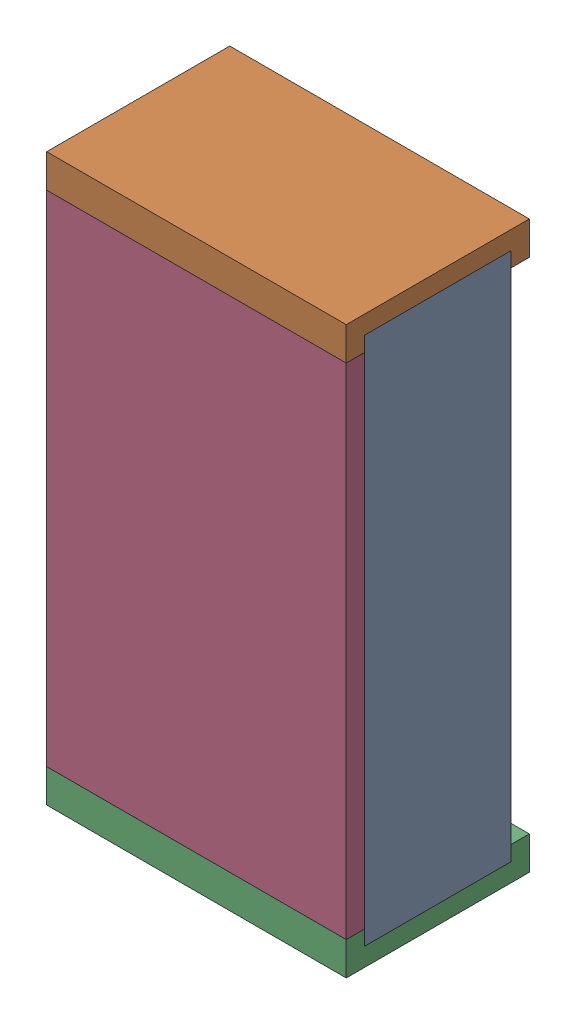
SolidWorks assembly R9, configuration Default. Lengths in mm.
Overall size (0.9 1.7 0.55).
7 component instances, 3 part files, 0 mates.
Components (placement in the parent):
- 6019289920-1: 6019289920 [Default] at (27.1701 -0.0001 0) x (0 -1 0) z (0 0 1) size (1.7 0.9 0.55)
  - Mid_Body_2-1: Mid_Body_2 [Default] at (-0.85 -0.45 0) size (1.59 0.9 0.44)
  - Terminal_2-1: Terminal_2 [Default] at (-0.85 -0.45 0) size (0.1 0.9 0.55)
    - Open CASCADE STEP translator 6.8 15.2.1_2-1: Open CASCADE STEP translator 6.8 15.2.1_2 [Default] at origin size (0.1 0.9 0.55)
  - Terminal_2-2: Terminal_2 [Default] at (0.85 0.45 0) x (-1 0 0) z (0 0 1) size (0.1 0.9 0.55)
    - Open CASCADE STEP translator 6.8 15.2.1_2-1: Open CASCADE STEP translator 6.8 15.2.1_2 [Default] at origin size (0.1 0.9 0.55)
  - Mark_2-1: Mark_2 [Default] at (-0.75 -0.45 0.495) size (1.5 0.9 0.06)
